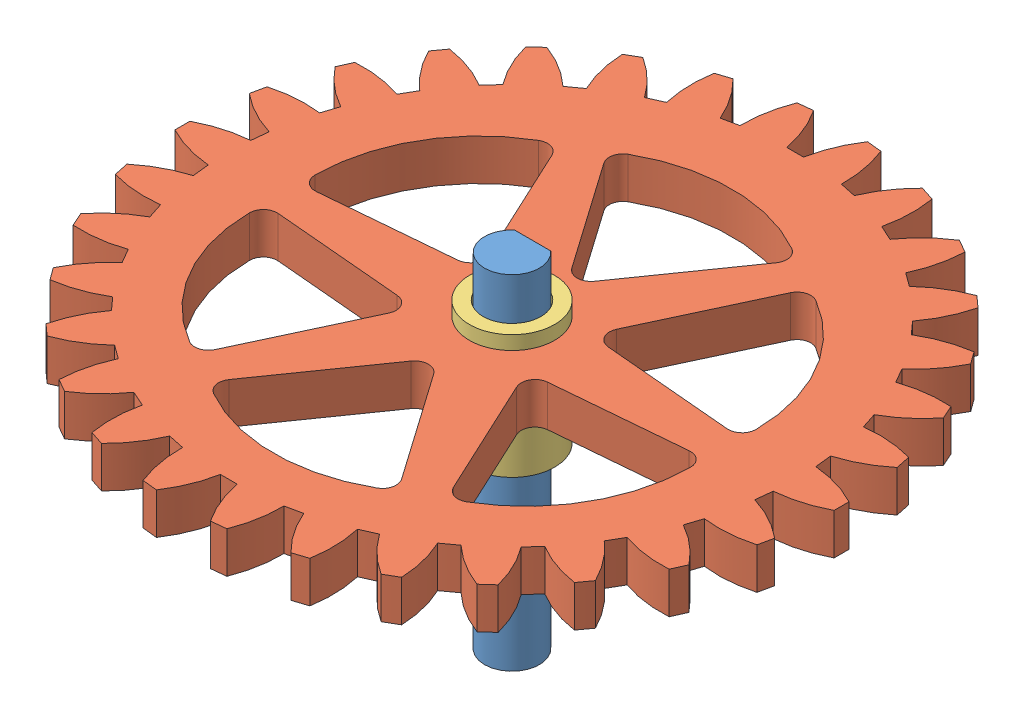
SolidWorks assembly subassem3, configuration Default. Lengths in mm.
Overall size (48 25 47.84).
4 component instances, 3 part files, 7 mates.
Components (placement in the parent):
- axel-1: axel [25 tall] at (12.3654 3.9053 23.7992) size (4 25 3.5)
- root_gear-1: root_gear [30T 1.5Mod] at (12.3654 21.9053 23.7992) size (48 3 47.84)
- spacer-1: spacer [1 mm tall] at (12.3654 24.9053 23.7992) x (0.97373 0 -0.227706) z (0.227706 0 0.97373) size (6.2 1 6.2)
- spacer-2: spacer [5mm tall] at (12.3654 16.9053 23.7992) size (6.2 5 6.2)
Mates (geometry in assembly coordinates):
- Concentric1: concentric: cylinder of axel-1 through (12.3654 28.9053 23.7992) axis (0 -1 0) radius 2; cylinder of root_gear-1 through (12.3654 21.9053 23.7992) axis (0 1 0) radius 2
- Coincident1: coincident: plane of axel-1 through (11.0426 28.9053 22.2992) normal (0 0 -1); plane of root_gear-1 through (13.6883 21.9053 22.2992) normal (0 0 1)
- Concentric2: concentric: cylinder of axel-1 through (12.3654 28.9053 23.7992) axis (0 -1 0) radius 2; cylinder of spacer-1 through (12.3654 24.9053 23.7992) axis (0 1 0) radius 2.1
- Concentric3: concentric: cylinder of axel-1 through (12.3654 28.9053 23.7992) axis (0 -1 0) radius 2; cylinder of spacer-2 through (12.3654 16.9053 23.7992) axis (0 1 0) radius 2.1
- Coincident2: coincident: plane of root_gear-1 through (12.3654 21.9053 23.7992) normal (0 -1 0); plane of spacer-2 through (12.3654 21.9053 23.7992) normal (0 1 0)
- Coincident3: coincident: plane of root_gear-1 through (12.3654 24.9053 23.7992) normal (0 1 0); plane of spacer-1 through (12.3654 24.9053 23.7992) normal (0 -1 0)
- Distance1: distance = 3 mm: plane of spacer-1 through (12.3654 25.9053 23.7992) normal (0 1 0); plane of axel-1 through (12.3654 28.9053 23.7992) normal (0 1 0)
